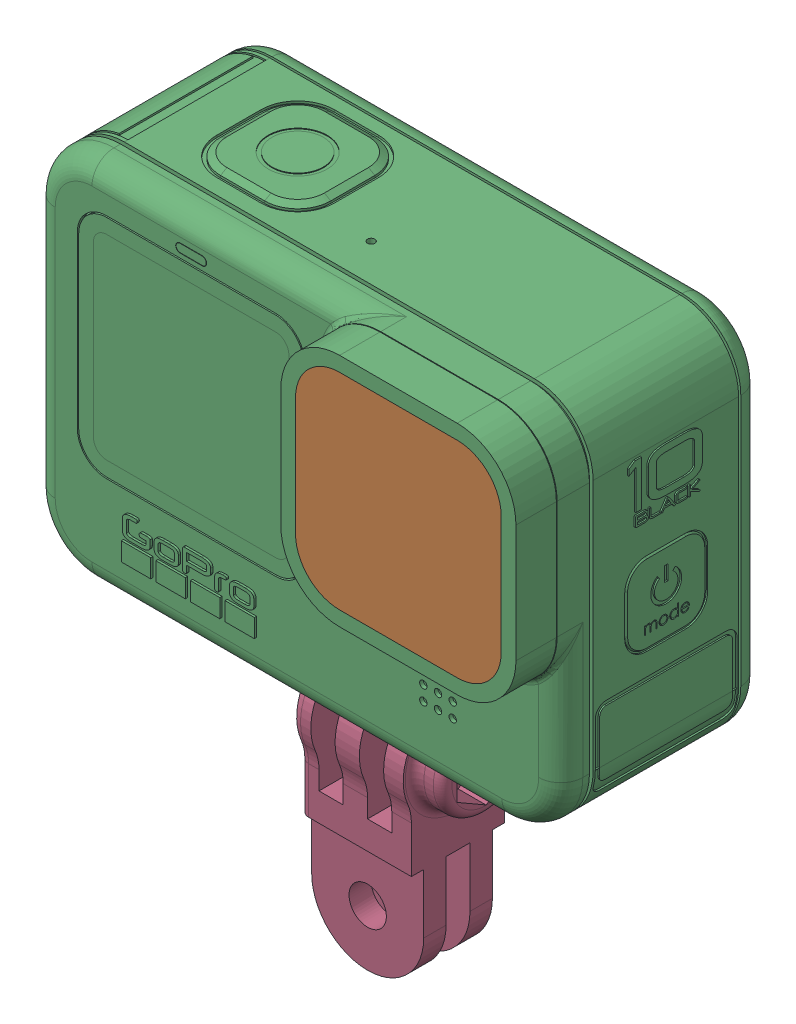
SolidWorks assembly gopro_assembly, configuration Default. Lengths in mm.
Overall size (72.3 86.8 33.6).
2 component instances, 2 part files, 3 mates.
Components (placement in the parent):
- go10 d2-1: go10 d2 [По умолчанию] at (-0.8666 11.5188 -24.3119) size (72.3 50.8 33.6)
- Modular Arm - Short 90 Member-1: Modular Arm - Short 90 Member [Default] at (6.7534 -33.9312 -11.1119) size (19.05 34.91 14.92)
Mates (geometry in assembly coordinates):
- Width1: width: plane of go10 d2-1 through (-5.8666 -8.6312 -8.1119) normal (-1 0 0); plane of Modular Arm - Short 90 Member-1 through (4.1334 -8.6312 -8.1119) normal (1 0 0); plane of go10 d2-1 through (-5.8196 -30.1212 -18.5732) normal (1 0 0); plane of Modular Arm - Short 90 Member-1 through (4.0864 -30.1212 -18.5732) normal (-1 0 0)
- Distance1: distance = 36 mm: point of assembly; plane of assembly; moEndPointRef_w of Modular Arm - Short 90 Member-1; plane of go10 d2-1 through (-28.7666 -13.6312 3.6881) normal (0 -1 0)
- Width2: width anti-aligned: plane of Modular Arm - Short 90 Member-1 through (-8.4866 -33.9312 -4.7619) normal (0 0 1); plane of go10 d2-1 through (-8.4866 -33.9312 -17.4619) normal (0 0 -1); plane of Modular Arm - Short 90 Member-1 through (-2.8666 -8.6312 -14.1119) normal (0 0 -1); plane of go10 d2-1 through (-2.8666 -8.6312 -8.1119) normal (0 0 1)
